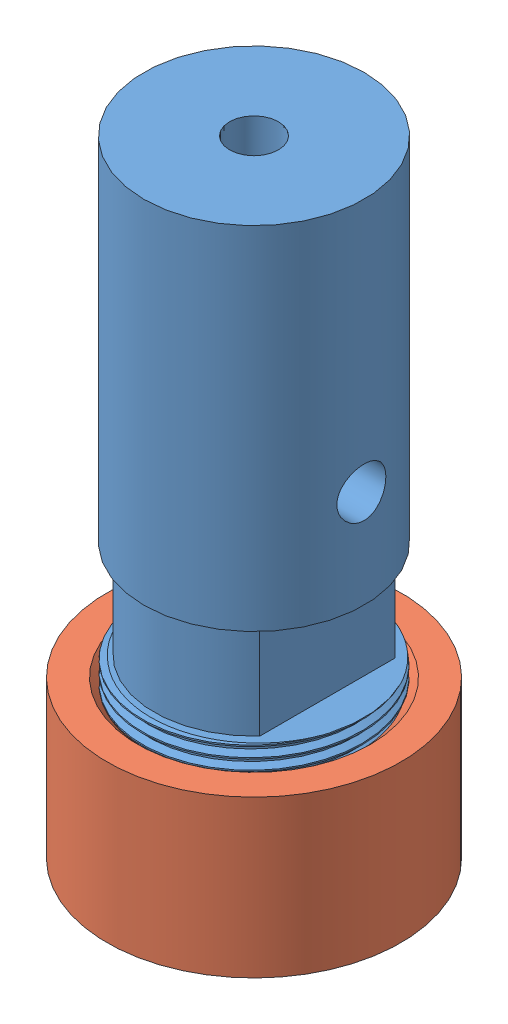
SolidWorks assembly Assem1, configuration Default. Lengths in mm.
Overall size (40.68 95.25 40.68).
2 component instances, 2 part files, 2 mates.
Components (placement in the parent):
- body1-1: body1 [Default] at (18.9831 17.1695 95.5859) size (29.76 95.25 29.44)
- clampring1-1: clampring1 [Default] at (18.9831 24.8911 95.5859) x (0.997542 0 -0.070065) z (0.070065 0 0.997542) size (38.1 20.38 38.1)
Mates (geometry in assembly coordinates):
- Concentric1: concentric: cylinder of body1-1 through (18.9831 67.8274 95.5859) axis (0 1 0) radius 14.2875; cylinder of clampring1-1 through (18.9831 42.4999 95.5859) axis (0 1 0) radius 19.05
- Distance1: distance = 6.223 mm: plane of clampring1-1 through (33.4889 28.8281 94.5671) normal (0 1 0); plane of body1-1 through (31.9371 35.0511 95.5859) normal (0 -1 0)
